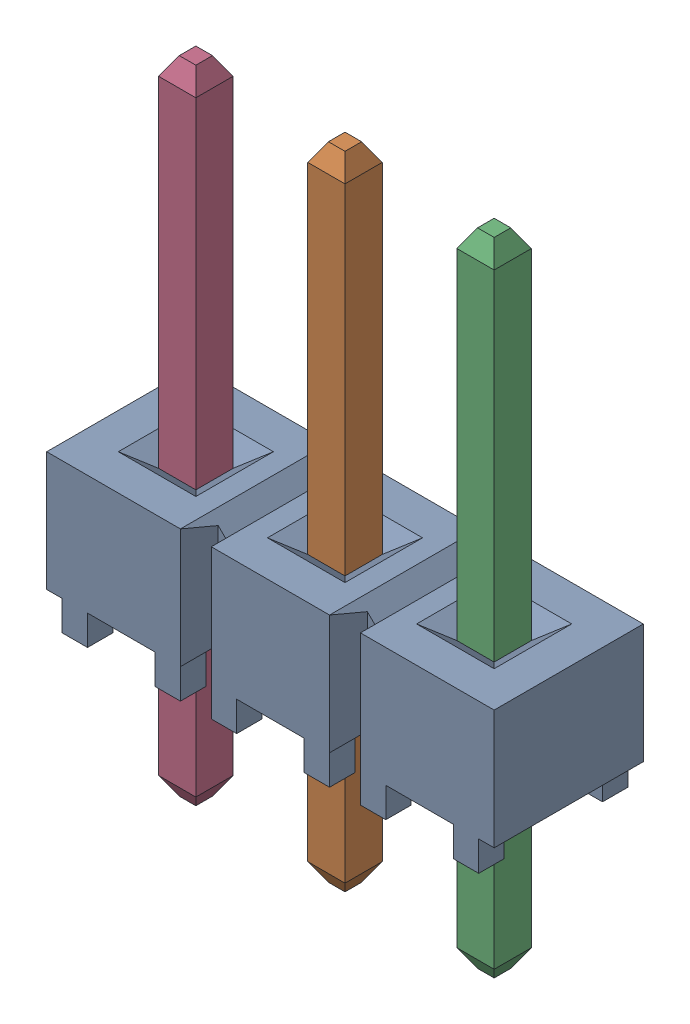
SolidWorks assembly C-L13-1X3_HEADER_ASM, configuration Default. Lengths in mm.
Overall size (7.62 10.92 2.54).
4 component instances, 2 part files, 0 mates.
Components (placement in the parent):
- C-HEADER-3PIN-BODY-1: C-HEADER-3PIN-BODY [Default] at origin size (7.62 2.54 2.54)
- C-T-HEADER-PIN-1: C-T-HEADER-PIN [Default] at (-6.35 -2.0599 0) x (0 0 1) z (-1 0 0) size (0.64 10.92 0.64)
- C-T-HEADER-PIN-2: C-T-HEADER-PIN [Default] at (-3.81 -2.0599 0) x (0 0 1) z (-1 0 0) size (0.64 10.92 0.64)
- C-T-HEADER-PIN-3: C-T-HEADER-PIN [Default] at (-8.89 -2.0599 0) x (0 0 1) z (-1 0 0) size (0.64 10.92 0.64)
